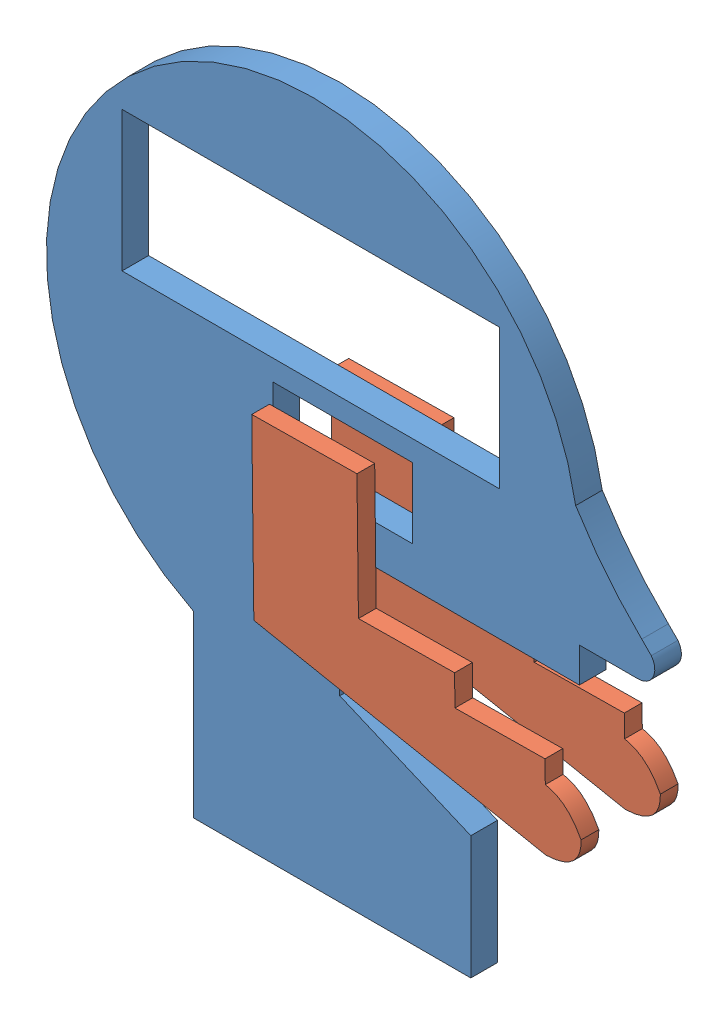
SolidWorks assembly Assem4, configuration Default. Lengths in mm.
Overall size (174.24 195.8 27.78).
3 component instances, 2 part files, 8 mates.
Components (placement in the parent):
- miray3-1: miray3 [Default] at origin size (174.24 195.8 7.62)
- miray4-1: miray4 [Default] at (-7.4277 -0.9967 12.62) x (0.99993 0.011806 0) z (0.011806 -0.99993 0) size (93.68 5.08 68.17)
- miray4-2: miray4 [Default] at (-7.4277 -0.9967 -10.08) x (0.99993 0.011806 0) z (0.011806 -0.99993 0) size (93.68 5.08 68.17)
Mates (geometry in assembly coordinates):
- Distance2: distance = 5 mm anti-aligned: plane of miray4-1 through (84.4871 -65.7837 12.62) normal (0 0 -1); plane of miray3-1 through (0 0 7.62) normal (0 0 1)
- Parallel5: parallel aligned: plane of miray4-1 through (23.0506 -30.2605 17.7) normal (0.99993 0.011806 0); plane of miray4-2 through (23.0506 -30.2605 -5) normal (0.99993 0.011806 0)
- Parallel6: parallel aligned: line of miray4-1 through (-6.8281 -51.7756 17.7) axis (0.981313 -0.19242 0); line of miray4-2 through (-6.8281 -51.7756 -5) axis (0.981313 -0.19242 0)
- Distance4: distance = 5 mm anti-aligned: plane of miray4-2 through (84.4871 -65.7837 -5) normal (0 0 1); plane of miray3-1 through (0 0 0) normal (0 0 -1)
- Parallel7: parallel aligned: line of miray4-1 through (22.7009 -0.641 12.62) axis (-0.99993 -0.011806 0); line of miray4-2 through (22.7009 -0.641 -10.08) axis (-0.99993 -0.011806 0)
- Parallel9: parallel aligned: line of miray4-1 through (22.7009 -0.641 12.62) axis (-0.99993 -0.011806 0); line of miray4-2 through (22.7009 -0.641 -5) axis (-0.99993 -0.011806 0)
- Coincident11: coincident aligned: plane of miray4-1 through (-7.4277 -0.9967 17.7) normal (-0.011806 0.99993 0); plane of miray4-2 through (-7.4277 -0.9967 -5) normal (-0.011806 0.99993 0)
- Coincident12: coincident: line of miray4-1 through (-7.4277 -0.9967 12.62) axis (0.011806 -0.99993 0); plane of miray4-2 through (-7.4277 -0.9967 -5) normal (-0.99993 -0.011806 0)
